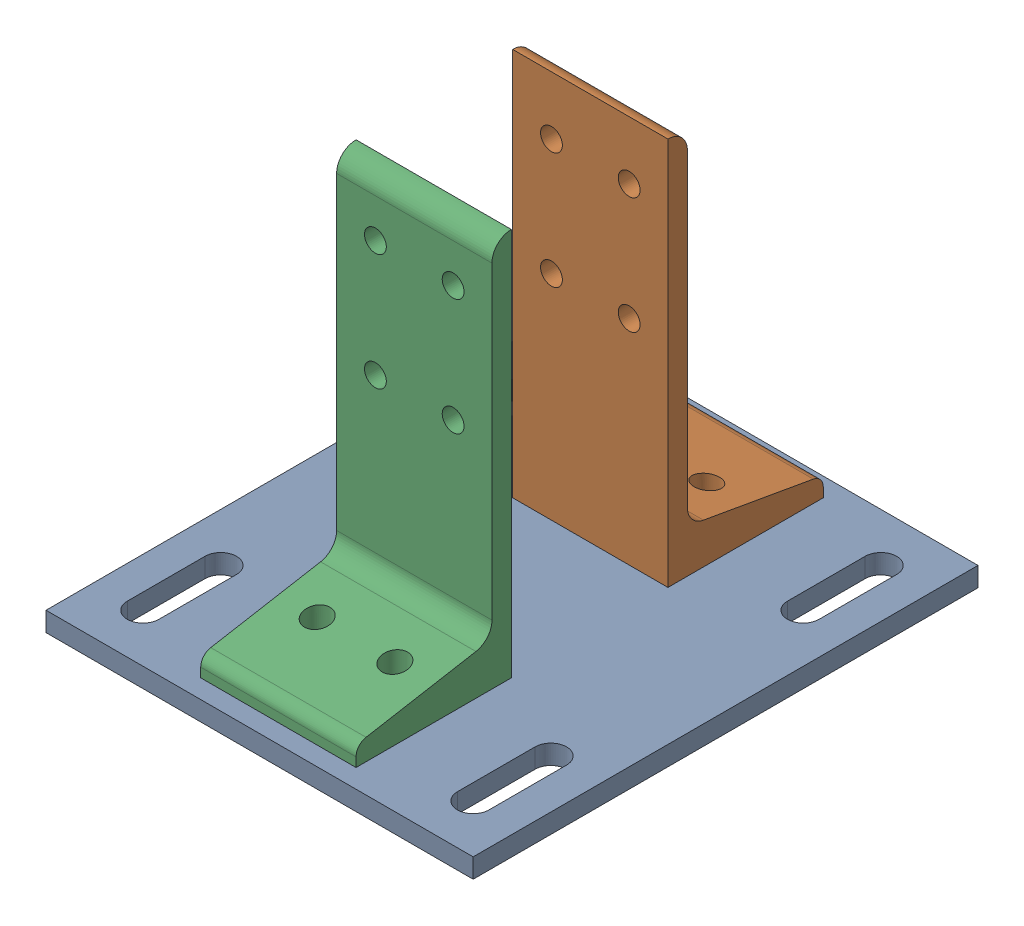
SolidWorks assembly Mirror8020-2387-DEFAULT2, configuration Default. Lengths in mm.
Overall size (139.7 133.35 165.1).
3 component instances, 2 part files, 0 mates.
Components (placement in the parent):
- Mirror8020-2387-DEFAULT_238708-1: Mirror8020-2387-DEFAULT_238708 [Default] at (-67.1549 7.3704 -27.8119) size (139.7 6.35 165.1)
- Mirror8020-2387-DEFAULT_238509-1: Mirror8020-2387-DEFAULT_238509 [Default] at (9.1264 0.0214 -49.7635) x (0 0 -1) z (1 0 0) size (50.8 127 50.8)
- Mirror8020-2387-DEFAULT_238509-2: Mirror8020-2387-DEFAULT_238509 [Default] at (-41.6736 0.0214 46.9187) x (0 0 1) z (-1 0 0) size (50.8 127 50.8)
